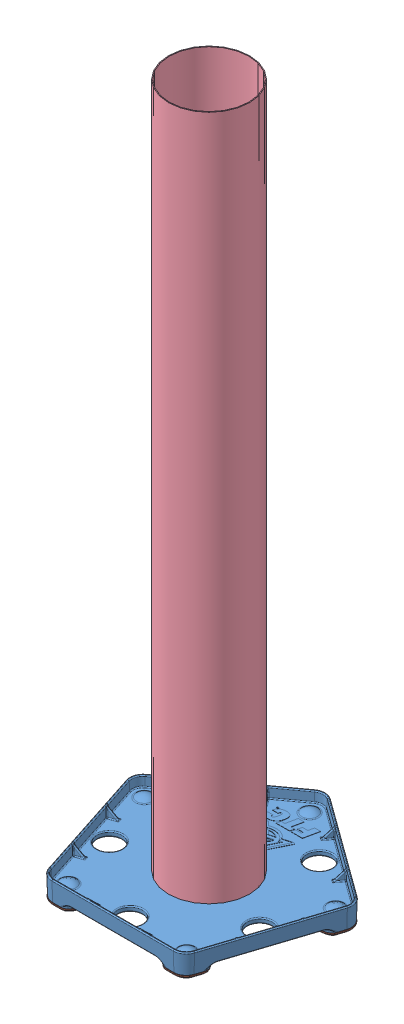
SolidWorks assembly Rolling_Goal-90cm, configuration Default. Lengths in mm.
Overall size (291.98 900.58 285.9).
12 component instances, 4 part files, 0 mates.
Components (placement in the parent):
- Final Rev1-2 - Pentagon Base-1: Final Rev1-2 - Pentagon Base [Default] at (-9.8868 20.1576 -8.4777) size (283.35 51.39 274.75)
- Final Rev1 - Pentagon Foot-1: Final Rev1 - Pentagon Foot [Default] at (-84.6377 13.8076 94.5082) x (0.809017 0 -0.587785) z (0.587785 0 0.809017) size (40.81 17.65 43.23)
- 1in Ball Caster-1: 1in Ball Caster [Default] at (-85.3501 20.1576 95.3886) size (25.4 25.4 25.4)
- Final Rev1 - Pentagon Foot-2: Final Rev1 - Pentagon Foot [Default] at (64.9593 13.8076 94.439) x (-0.309017 0 -0.951057) z (0.951057 0 -0.309017) size (40.81 17.65 43.23)
- Final Rev1 - Pentagon Foot-3: Final Rev1 - Pentagon Foot [Default] at (111.1214 13.8076 -47.8575) x (-1 0 0) z (0 0 -1) size (40.81 17.65 43.23)
- Final Rev1 - Pentagon Foot-4: Final Rev1 - Pentagon Foot [Default] at (-9.9457 13.8076 -135.7324) x (-0.309017 0 0.951057) z (-0.951057 0 -0.309017) size (40.81 17.65 43.23)
- Final Rev1 - Pentagon Foot-5: Final Rev1 - Pentagon Foot [Default] at (-130.9315 13.8076 -47.7455) x (0.809017 0 0.587785) z (-0.587785 0 0.809017) size (40.81 17.65 43.23)
- 1in Ball Caster-2: 1in Ball Caster [Default] at (65.5764 20.1576 95.3886) x (0.309017 0 -0.951057) z (0.951057 0 0.309017) size (25.4 25.4 25.4)
- 1in Ball Caster-3: 1in Ball Caster [Default] at (112.2152 20.1576 -48.151) x (-0.809017 0 -0.587785) z (0.587785 0 -0.809017) size (25.4 25.4 25.4)
- 1in Ball Caster-4: 1in Ball Caster [Default] at (-9.8868 20.1576 -136.8634) x (-0.809017 0 0.587785) z (-0.587785 0 -0.809017) size (25.4 25.4 25.4)
- 1in Ball Caster-5: 1in Ball Caster [Default] at (-131.9889 20.1576 -48.151) x (0.309017 0 0.951057) z (-0.951057 0 0.309017) size (25.4 25.4 25.4)
- Pipe - 90cm-1: Pipe - 90cm [Default] at (-9.8868 32.8576 -8.4777) size (103.63 874.6 103.63)
